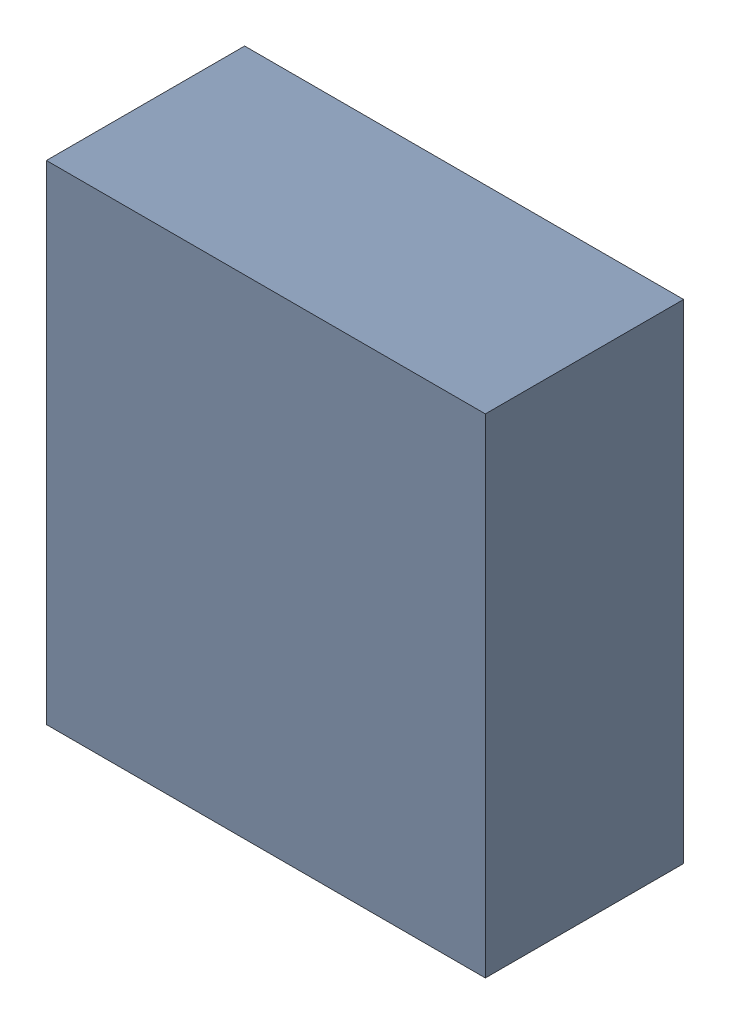
SolidWorks assembly F1_TDA1, configuration Standard. Lengths in mm.
Overall size (3.1 3.45 1.4).
2 component instances, 1 part files, 0 mates.
Components (placement in the parent):
- 885545096-1: 885545096 [Standard] at (-3.52 57.24 0) size (3.1 3.45 1.4)
  - Extruded_5-1: Extruded_5 [Standard] at origin size (3.1 3.45 1.4)
